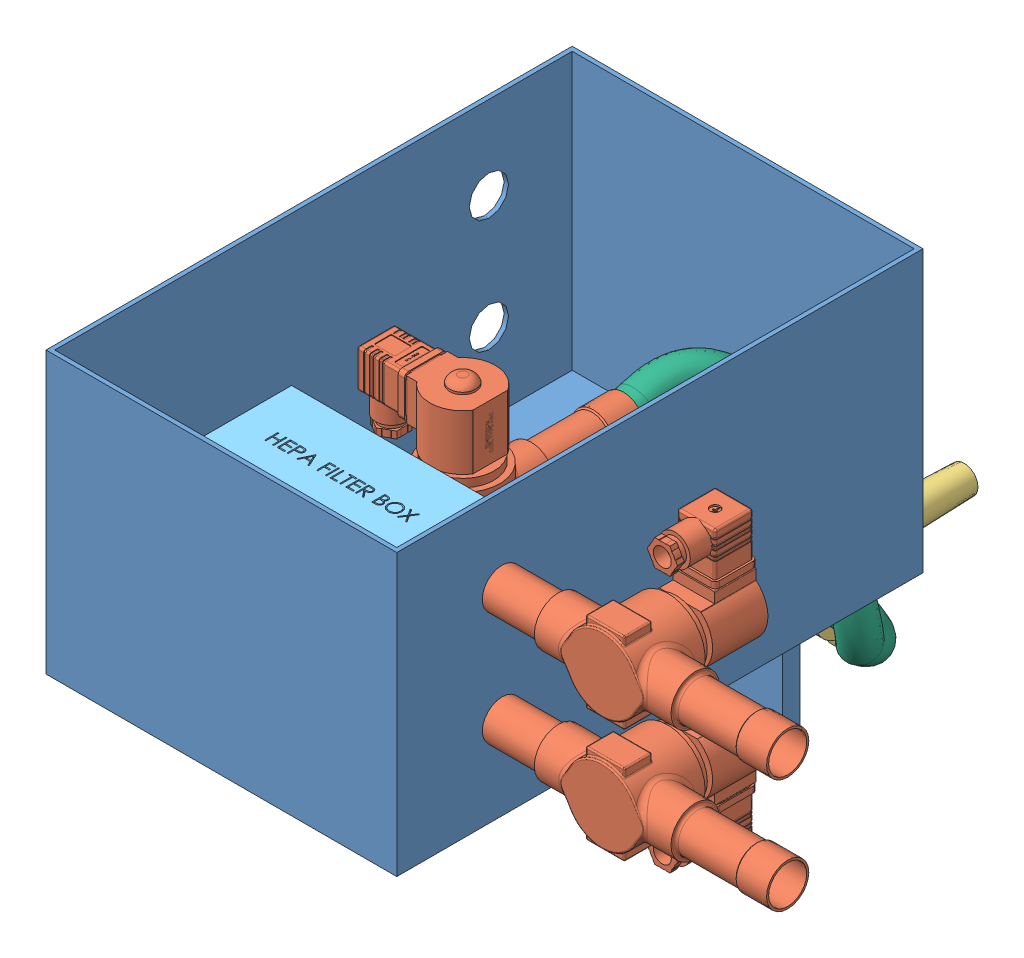
SolidWorks assembly PVP1_Mk1, configuration Default. Lengths in mm.
Overall size (460.83 332.88 530.83).
9 component instances, 6 part files, 16 mates.
Components (placement in the parent):
- AIR_BOX_TOTE_ASSY-1: AIR_BOX_TOTE_ASSY [Default] at (-70.4898 -99.1023 67.9924) size (254 330.2 381)
- 200RD9T9 - 1.1-8S  + BOBINA-1: 200RD9T9 - 1.1-8S  + BOBINA [Predeterminado] at (146.8352 -38.7773 182.2924) x (1 0 0) z (0 1 0) size (233 108.4 92.25)
- 200RD9T9 - 1.1-8S  + BOBINA-2: 200RD9T9 - 1.1-8S  + BOBINA [Predeterminado] at (146.8352 43.7727 182.2924) x (-1 0 0) z (0 -1 0) size (233 108.4 92.25)
- Flowmeter & Humidifier-1: Flowmeter & Humidifier [Default] at (-90.9532 -169.4636 -135.2713) x (-1 0 0) z (0 -1 0) size (107.26 292.29 78)
  - Flowmeter-1: Flowmeter [Default] at (-62.4634 14.0612 5.8387) size (107.26 256.21 67)
  - humidifier-1: humidifier [Default] at (-20.4634 -155.2272 5.8387) size (78 103.29 78)
- HEPA_FILTER_BOX-1: HEPA_FILTER_BOX [Default] at (-48.2648 2.4977 255.3174) x (1 0 0) z (0 1 0) size (152.4 101.6 127)
- 200RD9T9 - 1.1-8S  + BOBINA-3: 200RD9T9 - 1.1-8S  + BOBINA [Predeterminado] at (-48.2648 2.4977 105.9954) x (0 0 -1) z (1 0 0) size (233 108.4 92.25)
- POST_FILTER_PRE_HUMIDIFIER_HOSE-2: POST_FILTER_PRE_HUMIDIFIER_HOSE [Default] at (-6.8631 -79.7322 -79.7025) x (1 -0.000912 0) z (0 0 1) size (123.63 226.14 178.56)
Mates (geometry in assembly coordinates):
- Concentric1: concentric anti-aligned: circle of AIR_BOX_TOTE_ASSY-1; cylinder of 200RD9T9 - 1.1-8S  + BOBINA-2 through (52.3352 43.7727 182.2924) axis (-1 0 0) radius 15.3
- Concentric2: concentric anti-aligned: circle of AIR_BOX_TOTE_ASSY-1; cylinder of 200RD9T9 - 1.1-8S  + BOBINA-1 through (97.3352 -38.7773 182.2924) axis (-1 0 0) radius 14.3
- Coincident1: coincident anti-aligned: plane of AIR_BOX_TOTE_ASSY-1 through (53.3352 104.0977 -122.5076) normal (-1 0 0); circle of 200RD9T9 - 1.1-8S  + BOBINA-1
- Coincident2: coincident anti-aligned: plane of AIR_BOX_TOTE_ASSY-1 through (53.3352 104.0977 -122.5076) normal (-1 0 0); circle of 200RD9T9 - 1.1-8S  + BOBINA-2
- Parallel1: parallel anti-aligned: plane of 200RD9T9 - 1.1-8S  + BOBINA-1 through (146.8352 -18.7773 143.7424) normal (0 1 0); plane of 200RD9T9 - 1.1-8S  + BOBINA-2 through (146.8352 23.7727 143.7424) normal (0 -1 0)
- Parallel2: parallel anti-aligned: plane of 200RD9T9 - 1.1-8S  + BOBINA-2 through (146.8352 23.7727 143.7424) normal (0 -1 0)
- Coincident3: coincident anti-aligned: plane of AIR_BOX_TOTE_ASSY-1 through (-197.4898 104.0977 255.3174) normal (0 0 -1); plane of HEPA_FILTER_BOX-1 through (-48.2648 2.4977 255.3174) normal (0 0 1)
- Concentric3: concentric anti-aligned: cylinder of 200RD9T9 - 1.1-8S  + BOBINA-1 through (52.3352 -38.7773 182.2924) axis (-1 0 0) radius 15.3; cylinder of HEPA_FILTER_BOX-1 through (-22.8648 -38.7773 182.2924) axis (1 0 0) radius 19.25
- Concentric4: concentric aligned: cylinder of AIR_BOX_TOTE_ASSY-1 through (-70.4898 -175.3023 258.4934) axis (0 0 -1) radius 38.1; cylinder of Flowmeter & Humidifier-1/Flowmeter-1 through (-70.4898 -175.3023 -119.3326) axis (0 0 -1) radius 33.5
- Distance1: distance = 34.925 mm aligned: plane of Flowmeter & Humidifier-1/Flowmeter-1 through (-70.4898 -175.3023 -119.3326) normal (0 0 -1); plane of AIR_BOX_TOTE_ASSY-1 through (5.7102 -226.1023 -84.4076) normal (0 0 -1)
- Parallel3: parallel aligned: plane of AIR_BOX_TOTE_ASSY-1 through (5.7102 -226.1023 -84.4076) normal (1 0 0); plane of Flowmeter & Humidifier-1/Flowmeter-1 through (-28.4898 -175.3023 -149.3326) normal (1 0 0)
- Concentric5: concentric aligned: circle of HEPA_FILTER_BOX-1; circle of 200RD9T9 - 1.1-8S  + BOBINA-3
- Distance2: distance = 25.4 mm anti-aligned: plane of HEPA_FILTER_BOX-1 through (27.9352 -61.0023 153.7174) normal (1 0 0); plane of AIR_BOX_TOTE_ASSY-1 through (53.3352 104.0977 -122.5076) normal (-1 0 0)
- Distance3: distance = 61.722 mm aligned: plane of 200RD9T9 - 1.1-8S  + BOBINA-3 through (-19.0148 -3.2527 91.9954) normal (0 0 -1); plane of HEPA_FILTER_BOX-1 through (-48.2648 2.4977 153.7174) normal (0 0 -1)
- Parallel4: parallel aligned: plane of HEPA_FILTER_BOX-1 through (-124.4648 65.9977 153.7174) normal (0 1 0); plane of 200RD9T9 - 1.1-8S  + BOBINA-3 through (-80.2148 81.7354 93.2454) normal (0 1 0)
- Concentric9: concentric anti-aligned: cylinder of 200RD9T9 - 1.1-8S  + BOBINA-3 through (-48.2648 2.4977 11.4954) axis (0 0 -1) radius 15.3; cylinder of POST_FILTER_PRE_HUMIDIFIER_HOSE-2 through (-48.2648 2.4977 2.7745) axis (0 0 1) radius 12.5
